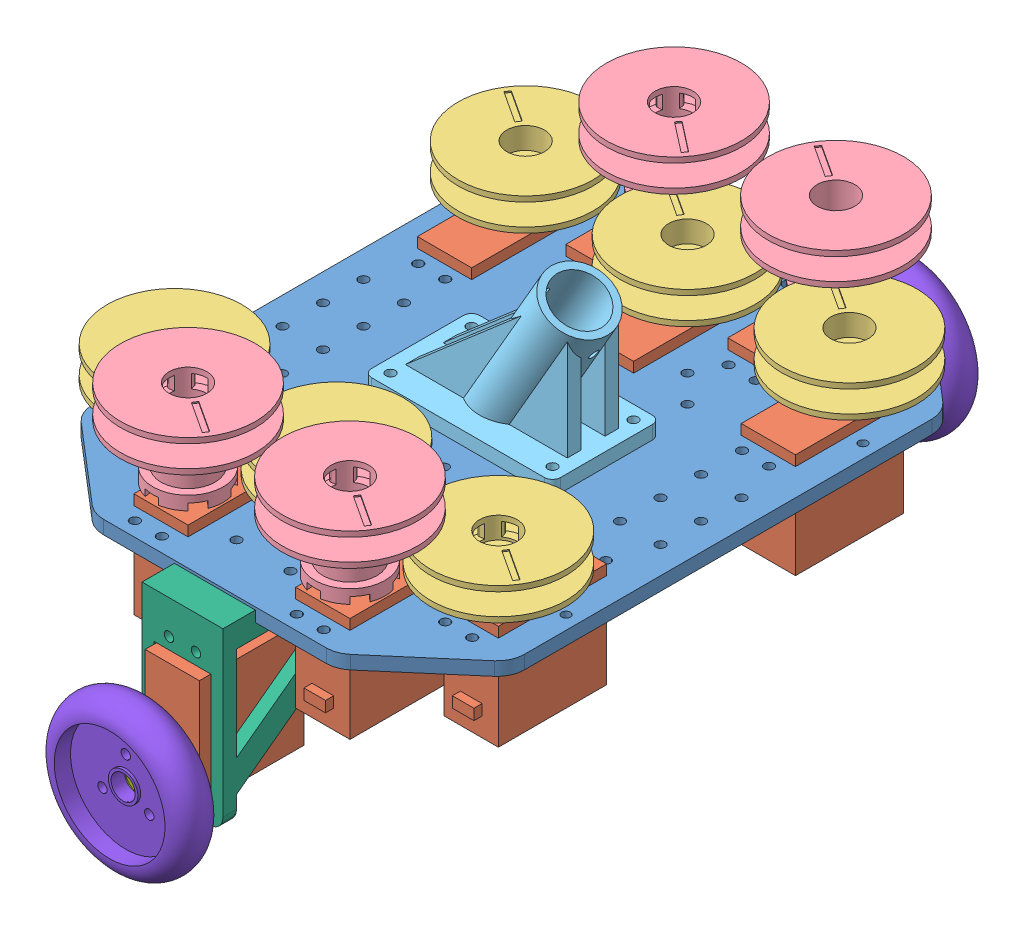
SolidWorks assembly base_motor, configuration ﾃﾞﾌｫﾙﾄ. Lengths in mm.
Overall size (192.73 130.6 298.2).
42 component instances, 8 part files, 48 mates.
Components (placement in the parent):
- base-1: base [ﾃﾞﾌｫﾙﾄ] at origin size (160.1 5 220.2)
- motor-1: motor [ﾃﾞﾌｫﾙﾄ] at (0 -30 -30.05) x (0 0 1) z (-1 0 0) size (73.36 59.5 70.97)
  - FB5311M-1: FB5311M [ﾃﾞﾌｫﾙﾄ] at origin size (54 44.25 20.1)
  - servo_horn_short-1: servo_horn_short [ﾃﾞﾌｫﾙﾄ] at (-10 42.5 0) x (-0.837169 0 -0.546944) z (0 1 0) size (50 57.04 17)
- motor-2: motor [ﾃﾞﾌｫﾙﾄ] at (-60 -30 -30.05) x (0 0 1) z (-1 0 0) size (73.36 59.5 70.97)
  - FB5311M-1: FB5311M [ﾃﾞﾌｫﾙﾄ] at origin size (54 44.25 20.1)
  - servo_horn_short-1: servo_horn_short [ﾃﾞﾌｫﾙﾄ] at (-10 42.5 0) x (-0.837169 0 -0.546944) z (0 1 0) size (50 57.04 17)
- motor-3: motor [ﾃﾞﾌｫﾙﾄ] at (60 -30 -30.05) x (0 0 1) z (-1 0 0) size (73.36 59.5 70.97)
  - FB5311M-1: FB5311M [ﾃﾞﾌｫﾙﾄ] at origin size (54 44.25 20.1)
  - servo_horn_short-1: servo_horn_short [ﾃﾞﾌｫﾙﾄ] at (-10 42.5 0) x (-0.837169 0 -0.546944) z (0 1 0) size (50 57.04 17)
- motor_long-6: motor_long [ﾃﾞﾌｫﾙﾄ] at (-30 -30 -55.05) x (0 0 1) z (-1 0 0) size (75.45 74.5 73.44) (flexible)
  - FB5311M-1: FB5311M [ﾃﾞﾌｫﾙﾄ] at origin size (54 44.25 20.1)
  - servo_horn_long-1: servo_horn_long [ﾃﾞﾌｫﾙﾄ] at (-10 42.5 0) x (0.789041 0 0.61434) z (0 1 0) size (50 57.04 32)
- motor_long-5: motor_long [ﾃﾞﾌｫﾙﾄ] at (30 -30 -55.05) x (0 0 1) z (-1 0 0) size (75.45 74.5 73.44)
  - FB5311M-1: FB5311M [ﾃﾞﾌｫﾙﾄ] at origin size (54 44.25 20.1)
  - servo_horn_long-1: servo_horn_long [ﾃﾞﾌｫﾙﾄ] at (-10 42.5 0) x (-0.837169 0 -0.546944) z (0 1 0) size (50 57.04 32)
- connector_45-1: connector_45 [ﾃﾞﾌｫﾙﾄ] at (0 10 25) x (0 0 1) z (0 1 0) size (40 70.39 54.3)
- motor-4: motor [ﾃﾞﾌｫﾙﾄ] at (-60 -30 80.05) x (0 0 -1) z (1 0 0) size (73.36 59.5 70.97)
  - FB5311M-1: FB5311M [ﾃﾞﾌｫﾙﾄ] at origin size (54 44.25 20.1)
  - servo_horn_short-1: servo_horn_short [ﾃﾞﾌｫﾙﾄ] at (-10 42.5 0) x (-0.837169 0 -0.546944) z (0 1 0) size (50 57.04 17)
- motor-5: motor [ﾃﾞﾌｫﾙﾄ] at (0 -30 80.05) x (0 0 -1) z (1 0 0) size (73.36 59.5 70.97)
  - FB5311M-1: FB5311M [ﾃﾞﾌｫﾙﾄ] at origin size (54 44.25 20.1)
  - servo_horn_short-1: servo_horn_short [ﾃﾞﾌｫﾙﾄ] at (-10 42.5 0) x (-0.837169 0 -0.546944) z (0 1 0) size (50 57.04 17)
- motor-6: motor [ﾃﾞﾌｫﾙﾄ] at (60 -30 80.05) x (0 0 -1) z (1 0 0) size (73.36 59.5 70.97)
  - FB5311M-1: FB5311M [ﾃﾞﾌｫﾙﾄ] at origin size (54 44.25 20.1)
  - servo_horn_short-1: servo_horn_short [ﾃﾞﾌｫﾙﾄ] at (-10 42.5 0) x (-0.837169 0 -0.546944) z (0 1 0) size (50 57.04 17)
- motor_long-7: motor_long [ﾃﾞﾌｫﾙﾄ] at (-30 -30 105.05) x (0 0 -1) z (1 0 0) size (75.45 74.5 73.44)
  - FB5311M-1: FB5311M [ﾃﾞﾌｫﾙﾄ] at origin size (54 44.25 20.1)
  - servo_horn_long-1: servo_horn_long [ﾃﾞﾌｫﾙﾄ] at (-10 42.5 0) x (-0.837169 0 -0.546944) z (0 1 0) size (50 57.04 32)
- motor_long-8: motor_long [ﾃﾞﾌｫﾙﾄ] at (30 -30 105.05) x (0 0 -1) z (1 0 0) size (75.45 74.5 73.44)
  - FB5311M-1: FB5311M [ﾃﾞﾌｫﾙﾄ] at origin size (54 44.25 20.1)
  - servo_horn_long-1: servo_horn_long [ﾃﾞﾌｫﾙﾄ] at (-10 42.5 0) x (-0.837169 0 -0.546944) z (0 1 0) size (50 57.04 32)
- wheel_motor-1: wheel_motor [ﾃﾞﾌｫﾙﾄ] at (15 -61.5 -92.1) x (-1 0 0) z (0 0 -1) size (56 75.3 72)
  - wheel_motor_mount-1: wheel_motor_mount [ﾃﾞﾌｫﾙﾄ] at origin size (30 65.5 45)
  - FB5311M-1: FB5311M [ﾃﾞﾌｫﾙﾄ] at (15 28.2 -30) x (0 1 0) z (1 0 0) size (54 44.25 20.1)
  - wheel_horn-1: wheel_horn [ﾃﾞﾌｫﾙﾄ] at (15 18.2 15.5) size (26 26 10.5)
  - tire-1: tire [ﾃﾞﾌｫﾙﾄ] at (15 18.2 24.5) x (0 0 -1) z (1 0 0) size (15 56 56)
- wheel_motor-2: wheel_motor [ﾃﾞﾌｫﾙﾄ] at (-15 -61.5 142.1) size (56 75.3 72)
  - wheel_motor_mount-1: wheel_motor_mount [ﾃﾞﾌｫﾙﾄ] at origin size (30 65.5 45)
  - FB5311M-1: FB5311M [ﾃﾞﾌｫﾙﾄ] at (15 28.2 -30) x (0 1 0) z (1 0 0) size (54 44.25 20.1)
  - wheel_horn-1: wheel_horn [ﾃﾞﾌｫﾙﾄ] at (15 18.2 15.5) size (26 26 10.5)
  - tire-1: tire [ﾃﾞﾌｫﾙﾄ] at (15 18.2 24.5) x (0 0 -1) z (1 0 0) size (15 56 56)
Mates (geometry in assembly coordinates):
- 同心円7: concentric aligned: cylinder of base-1 through (-25 0 -79.75) axis (0 1 0) radius 1.75; cylinder of motor_long-6/FB5311M-1 through (-25 -30 -79.75) axis (0 1 0) radius 2.25
- 同心円8: concentric aligned: cylinder of base-1 through (-35 0 -79.75) axis (0 1 0) radius 1.75; cylinder of motor-4/FB5311M-1 through (-35 -30 -79.75) axis (0 1 0) radius 2.25
- 同心円9: concentric aligned: cylinder of base-1 through (25 0 -79.75) axis (0 1 0) radius 1.75; cylinder of motor-5/FB5311M-1 through (25 -30 -79.75) axis (0 1 0) radius 2.25
- 同心円10: concentric aligned: cylinder of base-1 through (35 0 -79.75) axis (0 1 0) radius 1.75; cylinder of motor-5/FB5311M-1 through (35 -30 -79.75) axis (0 1 0) radius 2.25
- 同心円11: concentric aligned: cylinder of base-1 through (65 0 -54.75) axis (0 1 0) radius 1.75; cylinder of motor-3/FB5311M-1 through (65 -30 -54.75) axis (0 1 0) radius 2.25
- 同心円12: concentric aligned: cylinder of base-1 through (55 0 -54.75) axis (0 1 0) radius 1.75; cylinder of motor-3/FB5311M-1 through (55 -30 -54.75) axis (0 1 0) radius 2.25
- 同心円14: concentric aligned: cylinder of base-1 through (-5 0 -54.75) axis (0 1 0) radius 1.75; cylinder of motor-1/FB5311M-1 through (-5 -30 -54.75) axis (0 1 0) radius 2.25
- 同心円15: concentric aligned: cylinder of base-1 through (5 0 -54.75) axis (0 1 0) radius 1.75; cylinder of motor-1/FB5311M-1 through (5 -30 -54.75) axis (0 1 0) radius 2.25
- 同心円16: concentric aligned: cylinder of base-1 through (-55 0 -54.75) axis (0 1 0) radius 1.75; cylinder of motor-2/FB5311M-1 through (-55 -30 -54.75) axis (0 1 0) radius 2.25
- 同心円17: concentric aligned: cylinder of base-1 through (-65 0 -54.75) axis (0 1 0) radius 1.75; cylinder of motor-2/FB5311M-1 through (-65 -30 -54.75) axis (0 1 0) radius 2.25
- 同心円18: concentric aligned: cylinder of base-1 through (30 0 -10) axis (0 1 0) radius 1.75; cylinder of base_wire_connector-1 through (30 5 -10) axis (0 1 0) radius 1.75
- 同心円19: concentric aligned: cylinder of base-1 through (-30 0 -10) axis (0 1 0) radius 1.75; cylinder of base_wire_connector-1 through (-30 5 -10) axis (0 1 0) radius 1.75
- 一致6: coincident anti-aligned: plane of base-1 through (0 5 50) normal (0 1 0); plane of base_wire_connector-1 through (-15 5 0) normal (0 -1 0)
- 同心円20: concentric anti-aligned: cylinder of base-1 through (10 0 -67.1) axis (0 1 0) radius 1.75; cylinder of wheel_support-1 through (10 0 -67.1) axis (0 -1 0) radius 1.65
- 同心円21: concentric anti-aligned: cylinder of base-1 through (-10 0 -67.1) axis (0 1 0) radius 1.75; cylinder of wheel_support-1 through (-10 0 -67.1) axis (0 -1 0) radius 1.65
- 一致7: coincident anti-aligned: plane of base-1 through (0 0 50) normal (0 -1 0); plane of wheel_support-1 through (0 0 -67.1) normal (0 1 0)
- 一致8: coincident anti-aligned: plane of base-1 through (0 0 50) normal (0 -1 0); plane of motor-2/FB5311M-1 through (-60 0 -30.05) normal (0 1 0)
- 一致9: coincident anti-aligned: plane of base-1 through (0 0 50) normal (0 -1 0); plane of motor_long-6/FB5311M-1 through (-30 0 -55.05) normal (0 1 0)
- 一致10: coincident anti-aligned: plane of base-1 through (0 0 50) normal (0 -1 0); plane of motor-1/FB5311M-1 through (0 0 -30.05) normal (0 1 0)
- 一致11: coincident anti-aligned: plane of base-1 through (0 0 50) normal (0 -1 0); plane of motor_long-5/FB5311M-1 through (30 0 -55.05) normal (0 1 0)
- 一致12: coincident anti-aligned: plane of base-1 through (0 0 50) normal (0 -1 0); plane of motor-3/FB5311M-1 through (60 0 -30.05) normal (0 1 0)
- 同心円22: concentric anti-aligned: cylinder of base-1 through (-30 0 10) axis (0 1 0) radius 1.75; cylinder of connector_45-1 through (-30 59.3023 10) axis (0 -1 0) radius 1.75
- 同心円23: concentric anti-aligned: cylinder of base-1 through (30 0 10) axis (0 1 0) radius 1.75; cylinder of connector_45-1 through (30 59.3023 10) axis (0 -1 0) radius 1.75
- 一致13: coincident anti-aligned: plane of base-1 through (0 5 50) normal (0 1 0); plane of connector_45-1 through (0 5 25) normal (0 -1 0)
- 同心円24: concentric aligned: cylinder of base-1 through (-65 0 104.75) axis (0 1 0) radius 1.75; cylinder of motor-4/FB5311M-1 through (-65 -30 104.75) axis (0 1 0) radius 2.25
- 同心円25: concentric aligned: cylinder of base-1 through (-55 0 104.75) axis (0 1 0) radius 1.75; cylinder of motor-4/FB5311M-1 through (-55 -30 104.75) axis (0 1 0) radius 2.25
- 同心円27: concentric aligned: cylinder of base-1 through (5 0 104.75) axis (0 1 0) radius 1.75; cylinder of motor-5/FB5311M-1 through (5 -30 104.75) axis (0 1 0) radius 2.25
- 同心円28: concentric aligned: cylinder of base-1 through (-5 0 104.75) axis (0 1 0) radius 1.75; cylinder of motor-5/FB5311M-1 through (-5 -30 104.75) axis (0 1 0) radius 2.25
- 一致15: coincident anti-aligned: plane of base-1 through (0 0 50) normal (0 -1 0); plane of motor-5/FB5311M-1 through (0 0 80.05) normal (0 1 0)
- 同心円29: concentric aligned: cylinder of base-1 through (65 0 104.75) axis (0 1 0) radius 1.75; cylinder of motor-6/FB5311M-1 through (65 -30 104.75) axis (0 1 0) radius 2.25
- 同心円30: concentric aligned: cylinder of base-1 through (55 0 104.75) axis (0 1 0) radius 1.75; cylinder of motor-6/FB5311M-1 through (55 -30 104.75) axis (0 1 0) radius 2.25
- 一致16: coincident anti-aligned: plane of base-1 through (0 0 50) normal (0 -1 0); plane of motor-6/FB5311M-1 through (60 0 80.05) normal (0 1 0)
- 同心円31: concentric aligned: cylinder of base-1 through (-25 0 129.75) axis (0 1 0) radius 1.75; cylinder of motor_long-7/FB5311M-1 through (-25 -30 129.75) axis (0 1 0) radius 2.25
- 同心円32: concentric aligned: cylinder of base-1 through (-35 0 129.75) axis (0 1 0) radius 1.75; cylinder of motor_long-7/FB5311M-1 through (-35 -30 129.75) axis (0 1 0) radius 2.25
- 一致17: coincident anti-aligned: plane of base-1 through (0 0 50) normal (0 -1 0); plane of motor_long-7/FB5311M-1 through (-30 0 105.05) normal (0 1 0)
- 同心円33: concentric aligned: cylinder of base-1 through (25 0 129.75) axis (0 1 0) radius 1.75; cylinder of motor_long-8/FB5311M-1 through (25 -30 129.75) axis (0 1 0) radius 2.25
- 同心円34: concentric aligned: cylinder of base-1 through (35 0 129.75) axis (0 1 0) radius 1.75; cylinder of motor_long-8/FB5311M-1 through (35 -30 129.75) axis (0 1 0) radius 2.25
- 一致18: coincident anti-aligned: plane of base-1 through (0 0 50) normal (0 -1 0); plane of motor_long-8/FB5311M-1 through (30 0 105.05) normal (0 1 0)
- 同心円35: concentric anti-aligned: cylinder of base-1 through (10 0 117.1) axis (0 1 0) radius 1.75; cylinder of wheel_support-2 through (10 0 117.1) axis (0 -1 0) radius 1.65
- 同心円36: concentric anti-aligned: cylinder of base-1 through (-10 0 117.1) axis (0 1 0) radius 1.75; cylinder of wheel_support-2 through (-10 0 117.1) axis (0 -1 0) radius 1.65
- 一致19: coincident anti-aligned: plane of base-1 through (0 0 50) normal (0 -1 0); plane of wheel_support-2 through (0 0 117.1) normal (0 1 0)
- 一致20: coincident anti-aligned: plane of base-1 through (0 0 50) normal (0 -1 0); plane of motor-4/FB5311M-1 through (-60 0 80.05) normal (0 1 0)
- 同心円37: concentric aligned: cylinder of base-1 through (-10 0 -67.1) axis (0 1 0) radius 1.75; cylinder of wheel_motor-1/wheel_motor_mount-1 through (-10 -61.5 -67.1) axis (0 1 0) radius 1.75
- 同心円38: concentric aligned: cylinder of base-1 through (10 0 -67.1) axis (0 1 0) radius 1.75; cylinder of wheel_motor-1/wheel_motor_mount-1 through (10 -61.5 -67.1) axis (0 1 0) radius 1.75
- 一致21: coincident anti-aligned: plane of base-1 through (0 0 50) normal (0 -1 0); plane of wheel_motor-1/wheel_motor_mount-1 through (15 0 -97.1) normal (0 1 0)
- 同心円39: concentric aligned: cylinder of base-1 through (10 0 117.1) axis (0 1 0) radius 1.75; cylinder of wheel_motor-2/wheel_motor_mount-1 through (10 -61.5 117.1) axis (0 1 0) radius 1.75
- 同心円40: concentric aligned: cylinder of base-1 through (-10 0 117.1) axis (0 1 0) radius 1.75; cylinder of wheel_motor-2/wheel_motor_mount-1 through (-10 -61.5 117.1) axis (0 1 0) radius 1.75
- 一致22: coincident anti-aligned: plane of base-1 through (0 0 50) normal (0 -1 0); plane of wheel_motor-2/wheel_motor_mount-1 through (-15 0 147.1) normal (0 1 0)
